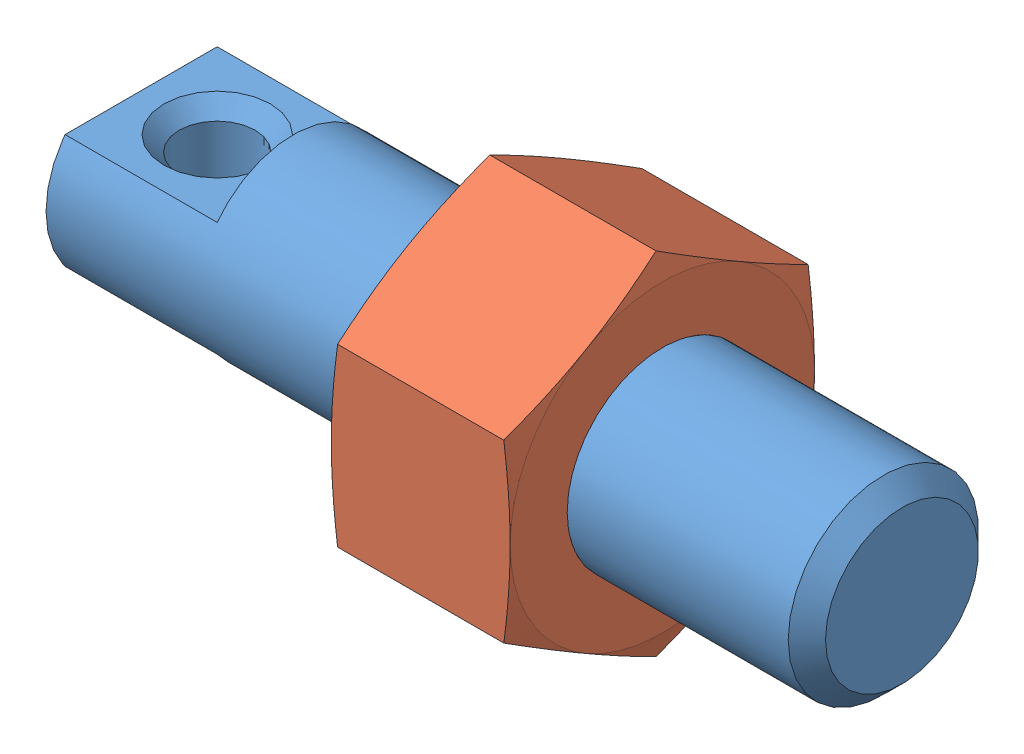
SolidWorks assembly Assem1, configuration Default. Lengths in mm.
Overall size (22.35 9.24 8).
2 component instances, 2 part files, 0 mates.
Components (placement in the parent):
- SAIPO5_20b-1: SAIPO5_20b [Default] at origin size (20 5 5)
- M5x0_8A-1: M5x0_8A [Default] at (11.35 0 0) x (-1 0 0) z (0 0 1) size (4.7 9.24 8)
